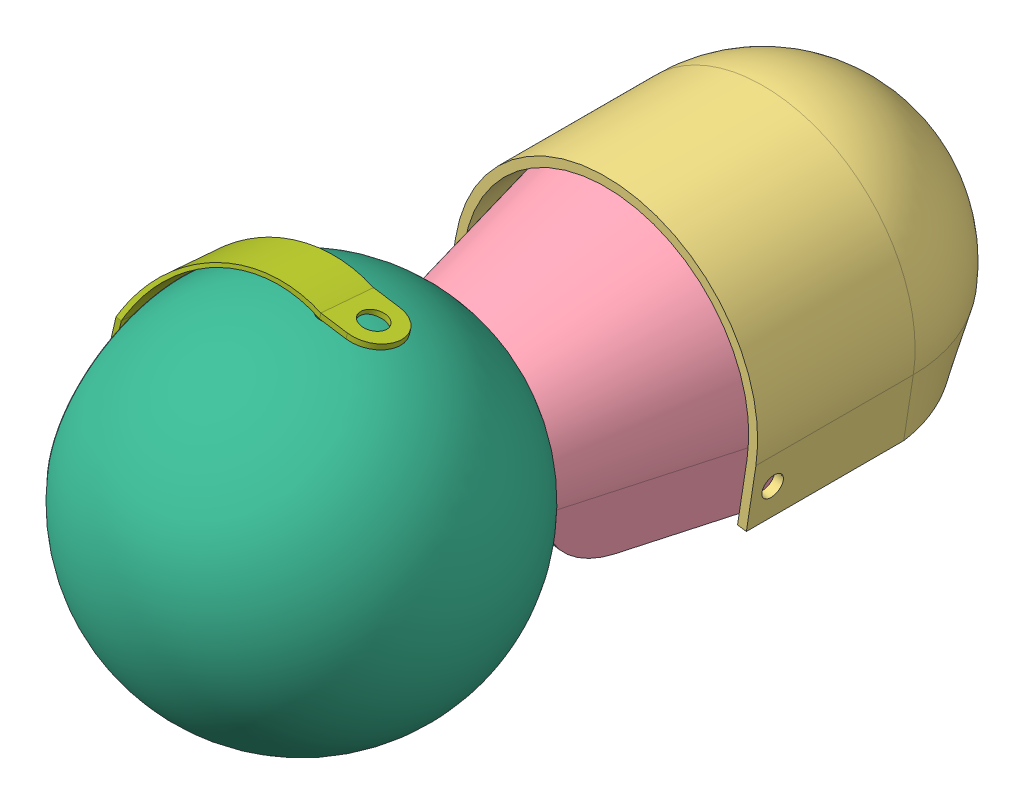
SolidWorks assembly Assem2, configuration Default. Lengths in mm.
Overall size (222.01 259.13 462.35).
10 component instances, 7 part files, 4 mates.
Components (placement in the parent):
- Assem1-2: Assem1 [Default] at (103.6691 94.8516 95.9274) size (100 50 170)
  - Base1-1: Base1 [Default] at (69.3133 102.1145 109.5236) size (100 37 170)
  - Top V2-1: Top V2 [Default] at (69.3133 144.6145 109.5236) x (-1 0 0) z (0 0 1) size (100 15 140)
- Body-1: Body [Default] at (20.0659 130.2208 244.079) x (0 0 -1) z (0.988247 -0.152865 0) size (259.01 120 170.02)
  - Back Shell-1: Back Shell [Default] at (10.2877 132.559 137.9644) size (209.01 120 170.02)
  - Front Shell-1: Front Shell [Default] at (20.2877 132.559 137.9644) size (180 115 160)
- Head-1: Head [Default] at (197.1451 277.8006 520.3681) x (-0.152318 -0.984708 0.084552) z (-0.012925 -0.083559 -0.996419) size (216.68 188.6 202.73)
  - Part2-1: Part2 [Default] at (19.0461 92.6358 93.1686) size (130 10 130)
  - Headshell-1: Headshell [Default] at (19.0461 15.3312 93.1686) x (-0.996419 0 -0.084552) z (0 1 0) size (201.64 186.35 178.3)
  - Eyes2-1: Eyes2 [Default] at (19.2177 -0.0714 92.7653) x (0 1 0) z (0.999923 0 -0.012375) size (118 44.77 210.57)
Mates (geometry in assembly coordinates):
- Coincident10: coincident: line of Body-1/Front Shell-1 through (226.0848 232.4887 343.7913) axis (-0.988247 0.152865 0); line of Head-1/Headshell-1 through (122.0553 259.2796 343.7913) axis (0.988247 -0.152865 0)
- Coincident12: coincident: circle of Body-1/Front Shell-1; circle of Head-1/Headshell-1
- Concentric12: concentric aligned: cylinder of Body-1/Front Shell-1 through (204.5715 249.477 343.7913) axis (0 0 -1) radius 7; cylinder of Head-1/Headshell-1 through (204.5715 249.477 363.7913) axis (0 0 -1) radius 7
- Coincident13: coincident aligned: circle of Body-1/Front Shell-1; circle of Head-1/Headshell-1
